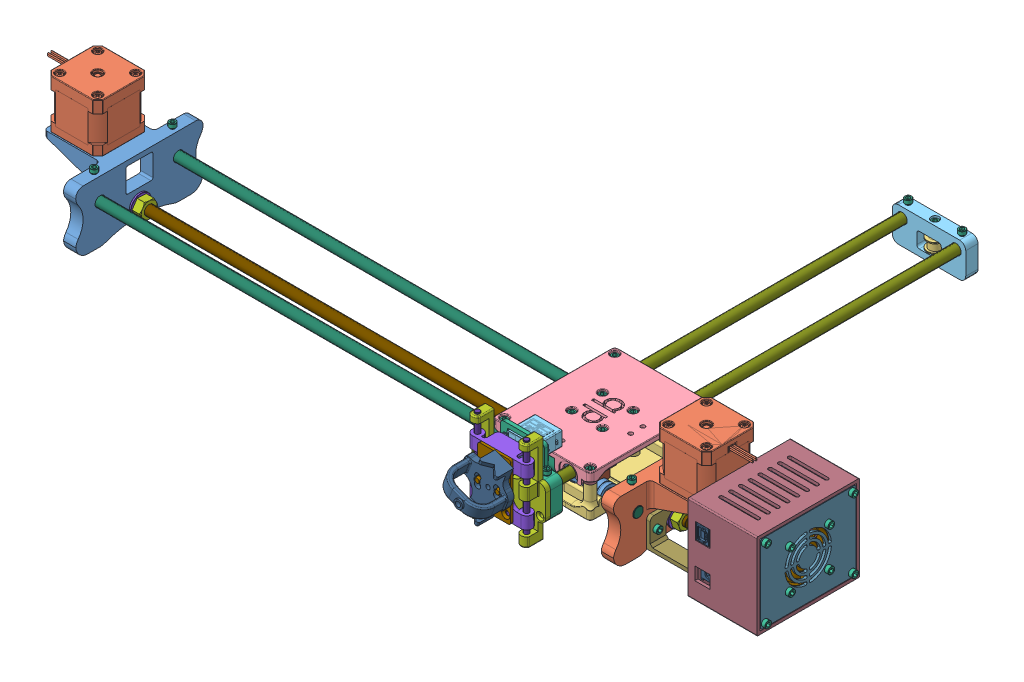
SolidWorks assembly DrawingBot, configuration 0. Lengths in mm.
Overall size (622.15 90 398.46).
88 component instances, 29 part files, 195 mates.
Components (placement in the parent):
- X_MotorHolder_R-1: X_MotorHolder_R [L=105] at (-219.5 73.7657 0) x (0 0 -1) z (1 0 0) size (103.98 50 56)
- X_MotorHolder_L-1: X_MotorHolder_L [L=105] at (219.5 73.7657 0) x (0 0 1) z (-1 0 0) size (103.98 50 56)
- Bottom_XY_Joint-1: Bottom_XY_Joint [L=105] at (163.5659 72.2657 0) x (0 0 -1) z (0 1 0) size (101.37 80.63 24)
- Top_XY_Joint-1: Top_XY_Joint [L=105] at (163.5659 106.2657 0) x (0 0 1) z (0 -1 0) size (100.63 81.5 12.75)
- Y_PullyHolder-1: Y_PullyHolder [L=105] at (163.5659 91.7657 -271.5357) x (-1 0 0) z (0 0 1) size (60 28 10)
- Y_FrontBacket-1: Y_FrontBacket [L=105] at (163.5659 91.7657 67.4643) size (60 46 10)
- Y_FrontBaseSlide-1: Y_FrontBaseSlide [L=105] at (163.5659 91.7657 74.4643) size (60 73 14)
- Y_Slider-1: Y_Slider [L=105] at (163.5659 98.6736 83.4643) size (49 46 14)
- slider-adapter-1: slider-adapter [L=105] at (163.5659 98.6736 87.4643) size (27 46 7)
- Pen_holder-1: Pen_holder [L=105] at (160.7688 99.7581 90.9643) x (-0.361491 -0.932376 0) z (0 0 1) size (46 38 29.5)
- linear bearing adapter-1: linear bearing adapter [L=105] at (185.5659 89.3657 32) x (0 0 -1) z (1 0 0) size (16 8 16)
- linear bearing adapter-2: linear bearing adapter [L=105] at (185.5659 89.3657 -32) x (0 0 -1) z (1 0 0) size (16 8 16)
- linear bearing adapter-6: linear bearing adapter [L=105] at (141.5659 89.3657 32) x (0 0 1) z (-1 0 0) size (16 8 16)
- linear bearing adapter-9: linear bearing adapter [L=105] at (141.5659 89.3657 -32) x (0 0 1) z (-1 0 0) size (16 8 16)
- ckt_Adapter-1: ckt_Adapter [L=105] at (226 74.7657 0) size (51 43.5 50)
- circuit-box-1: circuit-box [L=105] at (275.5 86.2657 0) x (0 0 -1) z (1 0 0) size (84 70 56)
- circuit-box-top-1: circuit-box-top [L=105] at (330.5 86.2657 0) x (0 0 1) z (-1 0 0) size (78 64 2.01)
- 8x450mm Rod-1: 8x450mm Rod [L=105] at (0 80.7657 32) x (0 0.981362 -0.192166) z (0 -0.192166 -0.981362) size (8 450 8)
- 8x450mm Rod-2: 8x450mm Rod [L=105] at (0 80.7657 -32) x (0 0.993096 -0.117304) z (0 -0.117304 -0.993096) size (8 450 8)
- 8x350mm Rod-1: 8x350mm Rod [L=105] at (141.5659 97.7657 -102.0357) x (0.82834 0.560225 0) z (-0.560225 0.82834 0) size (8 350 8)
- 8x350mm Rod-2: 8x350mm Rod [L=105] at (185.5659 97.7657 -102.0357) x (0.936223 -0.351406 0) z (0.351406 0.936223 0) size (8 350 8)
- 4x75mm Rod-1: 4x75mm Rod [L=105] at (143.5659 99.2657 81.9643) x (-0.999809 0 -0.019547) z (0.019547 0 -0.999809) size (4 75 4)
- 4x75mm Rod-2: 4x75mm Rod [L=105] at (183.5659 99.2657 81.9643) size (4 75 4)
- 8x470mm Threaded Rod-1: 8x470mm Threaded Rod [L=105] at (0 62.7657 0) x (0 -0.602738 0.797939) z (0 -0.797939 -0.602738) size (8 470 8)
- LM8UU-1: LM8UU [Default] at (188.8159 80.7657 -32) x (0 -0.1647 0.986344) z (-1 0 0) size (15 15 24)
- LM8UU-2: LM8UU [Default] at (138.3159 80.7657 -32) x (0 -0.602156 -0.798379) z (-1 0 0) size (15 15 24)
- LM8UU-3: LM8UU [Default] at (188.8159 80.7657 32) x (0 -0.991929 0.126791) z (-1 0 0) size (15 15 24)
- LM8UU-4: LM8UU [Default] at (138.3159 80.7657 32) x (0 -0.855569 0.517688) z (-1 0 0) size (15 15 24)
- LM8UU-5: LM8UU [Default] at (185.5659 97.7657 -35.25) x (0.052546 0.998619 0) z (0 0 -1) size (15 15 24)
- LM8UU-6: LM8UU [Default] at (185.5659 97.7657 35.25) x (-0.150221 0.988652 0) z (0 0 -1) size (15 15 24)
- LM8UU-7: LM8UU [Default] at (141.5659 97.7657 -35.25) x (-0.93295 0.360005 0) z (0 0 -1) size (15 15 24)
- LM8UU-8: LM8UU [Default] at (141.5659 97.7657 35.25) x (0.903307 0.428994 0) z (0 0 -1) size (15 15 24)
- Nema17-1: Nema17 [L=105] at (-248.5 138.7657 0) x (0 0 -1) z (0 -1 0) size (42.32 60.31 63.01)
- Nema17-2: Nema17 [L=105] at (248.5 138.7657 0) x (0 0 1) z (0 -1 0) size (42.32 60.31 63.01)
- GT2 Teethless Idler-Pulley 16TB3-1: GT2 Teethless Idler-Pulley 16TB3 [L=105] at (151.0659 89.2657 -12.5) x (-0.336139 0 0.941813) z (-0.941813 0 -0.336139) size (13 8.5 13)
- GT2 Teethless Idler-Pulley 16TB3-2: GT2 Teethless Idler-Pulley 16TB3 [L=105] at (151.0659 89.2657 12.5) x (0.130201 0 -0.991488) z (0.991488 0 0.130201) size (13 8.5 13)
- GT2 Teethless Idler-Pulley 16TB3-3: GT2 Teethless Idler-Pulley 16TB3 [L=105] at (176.0659 89.2657 12.5) x (0.290524 0 0.956868) z (-0.956868 0 0.290524) size (13 8.5 13)
- GT2 Teethless Idler-Pulley 16TB3-4: GT2 Teethless Idler-Pulley 16TB3 [L=105] at (176.0659 89.2657 -12.5) x (-0.336139 0 0.941813) z (-0.941813 0 -0.336139) size (13 8.5 13)
- GT2 Teethless Idler-Pulley 16TB3-5: GT2 Teethless Idler-Pulley 16TB3 [L=105] at (163.5659 89.2657 -271.5357) x (0.531082 0 -0.84732) z (0.84732 0 0.531082) size (13 8.5 13)
- GT Pulley T16-1: GT Pulley T16 [Default] at (-248.5 86.7657 0) x (-0.123537 0 -0.99234) z (0 1 0) size (13 13 14)
- GT Pulley T16-2: GT Pulley T16 [Default] at (248.5 86.7657 0) x (-0.763013 0 0.646383) z (0 1 0) size (13 13 14)
- SG90 - Micro Servo 9g - Tower Pro-3: SG90 - Micro Servo 9g - Tower Pro [L=105] at (170.2392 86.2325 37.9966) x (-1 0 0) z (0 1 0) size (32.5 32.03 12.58)
- M3 SCB-22: M3 SCB [5] at (185.5659 109.7657 -271.5357) x (-0.953748 0 0.300607) z (0 1 0) size (5.5 5.5 8)
- M3 SCB-24: M3 SCB [5] at (141.5659 109.7657 -271.5357) x (-0.953748 0 0.300607) z (0 1 0) size (5.5 5.5 8)
- M3 SCB-26: M3 SCB [5] at (185.5659 109.7657 67.4643) x (-0.953748 0 0.300607) z (0 1 0) size (5.5 5.5 8)
- M3 SCB-28: M3 SCB [5] at (141.5659 109.7657 67.4643) x (-0.980909 0 0.194469) z (0 1 0) size (5.5 5.5 8)
- M3 SCB-10: M3 SCB [8] at (-264 92.7657 15.5) x (0.888777 0 0.458341) z (0 -1 0) size (5.5 5.5 11)
- M3 SCB-12: M3 SCB [8] at (-233 92.7657 15.5) x (0.969011 0 0.247016) z (0 -1 0) size (5.5 5.5 11)
- M3 SCB-14: M3 SCB [8] at (-233 92.7657 -15.5) x (0.998414 0 0.056289) z (0 -1 0) size (5.5 5.5 11)
- M3 SCB-16: M3 SCB [8] at (-264 92.7657 -15.5) x (0.995991 0 -0.089455) z (0 -1 0) size (5.5 5.5 11)
- M3 SCB-4: M3 SCB [8] at (233 92.7657 -15.5) x (0.38908 0 0.921204) z (0 -1 0) size (5.5 5.5 11)
- M3 SCB-6: M3 SCB [8] at (233 92.7657 15.5) x (0.578518 0 0.815669) z (0 -1 0) size (5.5 5.5 11)
- M3 SCB-46: M3 SCB [10] at (334.5 114.7657 35.5) x (0 -0.781175 -0.624312) z (1 0 0) size (5.5 5.5 13)
- M3 SCB-47: M3 SCB [10] at (334.5 114.7657 -35.5) x (0 -0.672307 -0.740273) z (1 0 0) size (5.5 5.5 13)
- M3 SCB-49: M3 SCB [10] at (334.5 57.7657 -35.5) x (0 -0.572574 -0.819853) z (1 0 0) size (5.5 5.5 13)
- M3 SCB-51: M3 SCB [10] at (334.5 57.7657 35.5) x (0 -0.493661 -0.869655) z (1 0 0) size (5.5 5.5 13)
- M3 SCB-3: M3 SCB [12] at (264 88.7657 -15.5) x (0.575249 0 0.817979) z (0 -1 0) size (5.5 5.5 15)
- M3 SCB-8: M3 SCB [12] at (264 88.7657 15.5) x (0.997731 0 0.067327) z (0 -1 0) size (5.5 5.5 15)
- M3 SCB-59: M3 SCB [14] at (230.5 64.7657 20) x (0 -0.34953 -0.936925) z (1 0 0) size (5.5 5.5 17)
- M3 SCB-60: M3 SCB [14] at (230.5 64.7657 -20) x (0 -0.34953 -0.936925) z (1 0 0) size (5.5 5.5 17)
- M3 SCB-53: M3 SCB [15] at (334.5 102.2657 -16) x (0 -0.672307 -0.740273) z (1 0 0) size (5.5 5.5 18)
- M3 SCB-54: M3 SCB [15] at (334.5 102.2657 16) x (0 -0.54643 -0.837505) z (1 0 0) size (5.5 5.5 18)
- M3 SCB-56: M3 SCB [15] at (334.5 70.2657 -16) x (0 -0.435341 -0.900266) z (1 0 0) size (5.5 5.5 18)
- M3 SCB-58: M3 SCB [15] at (334.5 70.2657 16) x (0 -0.34953 -0.936925) z (1 0 0) size (5.5 5.5 18)
- M3 SCB-1: M3 SCB [15] at (219.5 102.7657 32) x (-0.773306 0 -0.634033) z (0 1 0) size (5.5 5.5 18)
- M3 SCB-2: M3 SCB [15] at (219.5 102.7657 -32) x (-0.981919 0 0.189303) z (0 1 0) size (5.5 5.5 18)
- M3 SCB-18: M3 SCB [15] at (-219.5 102.7657 32) x (-0.878936 0 -0.476939) z (0 1 0) size (5.5 5.5 18)
- M3 SCB-20: M3 SCB [15] at (-219.5 102.7657 -32) x (-0.961086 0 -0.27625) z (0 1 0) size (5.5 5.5 18)
- M3 SCB-45: M3 SCB [25] at (163.5659 104.7657 -271.5357) x (-0.7545 0 0.6563) z (0 1 0) size (5.5 5.5 28)
- M3 SCB-30: M3 SCB [30] at (151.0659 105.2657 -12.5) x (-0.546321 0 0.837576) z (0 1 0) size (5.5 5.5 33)
- M3 SCB-31: M3 SCB [30] at (176.0659 105.2657 -12.5) x (-0.378687 0 0.925525) z (0 1 0) size (5.5 5.5 33)
- M3 SCB-33: M3 SCB [30] at (151.0659 105.2657 12.5) x (0.82864 0 -0.559782) z (0 1 0) size (5.5 5.5 33)
- M3 SCB-35: M3 SCB [30] at (176.0659 105.2657 12.5) x (0.065489 0 0.997853) z (0 1 0) size (5.5 5.5 33)
- M3 SCB-37: M3 SCB [30] at (128.5659 105.2657 -45) x (0.402386 0 0.91547) z (0 1 0) size (5.5 5.5 33)
- M3 SCB-39: M3 SCB [30] at (198.5659 105.2657 -45) x (0.402386 0 0.91547) z (0 1 0) size (5.5 5.5 33)
- M3 SCB-41: M3 SCB [30] at (198.5659 105.2657 45) x (0.402386 0 0.91547) z (0 1 0) size (5.5 5.5 33)
- M3 SCB-43: M3 SCB [30] at (128.5659 105.2657 45) x (0.402386 0 0.91547) z (0 1 0) size (5.5 5.5 33)
- LBNR8-1: LBNR8 [L=105] at (229.25 62.7657 0) x (-1 0 0) z (0 0.682259 0.73111) size (6.5 15 13)
- LBNR8-2: LBNR8 [L=105] at (209.75 62.7657 0) x (1 0 0) z (0 0.362627 0.931934) size (6.5 15 13)
- LBNR8-4: LBNR8 [L=105] at (-229.25 62.7657 0) x (1 0 0) z (0 0.47834 0.878175) size (6.5 15 13)
- LBNR8-6: LBNR8 [L=105] at (-209.75 62.7657 0) x (-1 0 0) z (0 0.553773 0.832668) size (6.5 15 13)
- M8-Washer-1: M8-Washer [L=105] at (225.25 62.7657 0) x (0 -0.998902 0.046855) z (-1 0 0) size (17 17 1.5)
- M8-Washer-2: M8-Washer [L=105] at (213.75 62.7657 0) x (0 0.973077 0.230481) z (1 0 0) size (17 17 1.5)
- M8-Washer-4: M8-Washer [L=105] at (-225.25 62.7657 0) x (0 0.994504 0.104701) z (1 0 0) size (17 17 1.5)
- M8-Washer-6: M8-Washer [L=105] at (-213.75 62.7657 0) x (0 -0.371154 0.928571) z (-1 0 0) size (17 17 1.5)
- 40x40x10 DC Fan-1: 40x40x10 DC Fan [Default] at (324.25 86.2657 0) x (0 0 1) z (-1 0 0) size (49.86 40.69 10.5)
- arduino uno-1: arduino uno [L=105] at (281.65 62.9657 35.94) x (0 -1 0) z (0 0 1) size (53.34 15.25 74.93)
- Arduino_Uno_CNC_Shield_V3-1: Arduino_Uno_CNC_Shield_V3 [Default] at (292.66 62.9657 35.94) x (0 0 -1) z (1 0 0) size (69 53.5 27.15)
Mates (geometry in assembly coordinates):
- Concentric1: concentric anti-aligned: cylinder of X_MotorHolder_L-1 through (214.5 80.7657 32) axis (1 0 0) radius 4.2; cylinder of 8x450mm Rod-1 through (225 80.7657 32) axis (-1 0 0) radius 4
- Concentric2: concentric anti-aligned: cylinder of X_MotorHolder_L-1 through (214.5 80.7657 -32) axis (1 0 0) radius 4.2; cylinder of 8x450mm Rod-2 through (225 80.7657 -32) axis (-1 0 0) radius 4
- Concentric3: concentric aligned: cylinder of X_MotorHolder_R-1 through (-214.5 80.7657 -32) axis (-1 0 0) radius 4.2; cylinder of 8x450mm Rod-2 through (225 80.7657 -32) axis (-1 0 0) radius 4
- Concentric4: concentric aligned: cylinder of X_MotorHolder_R-1 through (-214.5 80.7657 32) axis (-1 0 0) radius 4.2; cylinder of 8x450mm Rod-1 through (225 80.7657 32) axis (-1 0 0) radius 4
- Distance1: distance = 0.5 mm aligned: plane of 8x450mm Rod-2 through (225 80.7657 -32) normal (1 0 0); plane of X_MotorHolder_L-1 through (224.5 75.0486 -66) normal (1 0 0)
- Distance2: distance = 0.5 mm aligned: plane of 8x450mm Rod-1 through (225 80.7657 32) normal (1 0 0); plane of X_MotorHolder_L-1 through (224.5 75.0486 -66) normal (1 0 0)
- Distance3: distance = 0.5 mm aligned: plane of 8x450mm Rod-2 through (-225 80.7657 -32) normal (-1 0 0); plane of X_MotorHolder_R-1 through (-224.5 75.0486 66) normal (-1 0 0)
- Concentric5: concentric anti-aligned: cylinder of 8x450mm Rod-2 through (225 80.7657 -32) axis (-1 0 0) radius 4; cylinder of LM8UU-1 through (176.8159 80.7657 -32) axis (1 0 0) radius 4
- Concentric6: concentric anti-aligned: cylinder of 8x450mm Rod-2 through (225 80.7657 -32) axis (-1 0 0) radius 4; cylinder of LM8UU-2 through (126.3159 80.7657 -32) axis (1 0 0) radius 4
- Concentric7: concentric anti-aligned: cylinder of 8x450mm Rod-1 through (225 80.7657 32) axis (-1 0 0) radius 4; cylinder of LM8UU-3 through (176.8159 80.7657 32) axis (1 0 0) radius 4
- Concentric8: concentric anti-aligned: cylinder of 8x450mm Rod-1 through (225 80.7657 32) axis (-1 0 0) radius 4; cylinder of LM8UU-4 through (126.3159 80.7657 32) axis (1 0 0) radius 4
- Concentric9: concentric anti-aligned: cylinder of LM8UU-4 through (126.3159 80.7657 32) axis (1 0 0) radius 7.5; cylinder of Bottom_XY_Joint-1 through (196.9862 80.7657 32) axis (-1 0 0) radius 7.75
- Concentric10: concentric anti-aligned: cylinder of LM8UU-2 through (126.3159 80.7657 -32) axis (1 0 0) radius 7.5; cylinder of Bottom_XY_Joint-1 through (196.9862 80.7657 -32) axis (-1 0 0) radius 7.75
- Distance4: distance = 0.25 mm anti-aligned: plane of LM8UU-2 through (126.3159 80.7657 -32) normal (-1 0 0); plane of Bottom_XY_Joint-1 through (126.0659 81.4068 -35.2499) normal (1 0 0)
- Coincident7: coincident aligned: plane of LM8UU-2 through (126.3159 80.7657 -32) normal (-1 0 0); plane of LM8UU-4 through (126.3159 80.7657 32) normal (-1 0 0)
- Distance5: distance = 0.25 mm anti-aligned: plane of Bottom_XY_Joint-1 through (201.0659 81.4068 35.2499) normal (-1 0 0); plane of LM8UU-3 through (200.8159 80.7657 32) normal (1 0 0)
- Coincident9: coincident aligned: plane of LM8UU-1 through (200.8159 80.7657 -32) normal (1 0 0); plane of LM8UU-3 through (200.8159 80.7657 32) normal (1 0 0)
- Concentric11: concentric anti-aligned: cylinder of X_MotorHolder_R-1 through (-233 94.7657 15.5) axis (0 1 0) radius 1.75; cylinder of Nema17-1 through (-233 98.7657 15.5) axis (0 -1 0) radius 1.5
- Concentric12: concentric anti-aligned: cylinder of X_MotorHolder_R-1 through (-264 94.7657 -15.5) axis (0 1 0) radius 1.75; cylinder of Nema17-1 through (-264 98.7657 -15.5) axis (0 -1 0) radius 1.5
- Coincident10: coincident anti-aligned: plane of X_MotorHolder_R-1 through (-214.5 98.7657 52) normal (0 1 0); plane of Nema17-1 through (-248.5 98.7657 0) normal (0 -1 0)
- Concentric13: concentric anti-aligned: cylinder of X_MotorHolder_L-1 through (233 94.7657 15.5) axis (0 1 0) radius 1.75; cylinder of Nema17-2 through (233 98.7657 15.5) axis (0 -1 0) radius 1.5
- Concentric14: concentric anti-aligned: cylinder of X_MotorHolder_L-1 through (264 94.7657 -15.5) axis (0 1 0) radius 1.75; cylinder of Nema17-2 through (264 98.7657 -15.5) axis (0 -1 0) radius 1.5
- Coincident11: coincident anti-aligned: plane of X_MotorHolder_L-1 through (214.5 98.7657 -52) normal (0 1 0); plane of Nema17-2 through (248.5 98.7657 0) normal (0 -1 0)
- Concentric15: concentric aligned: cylinder of Nema17-1 through (-248.5 75.7657 0) axis (0 1 0) radius 2.5; cylinder of GT Pulley T16-1 through (-248.5 111.3534 0) axis (0 1 0) radius 2.5
- Distance6: distance = 4 mm aligned: plane of GT Pulley T16-1 through (-254.9502 79.7657 0.803) normal (0 -1 0); plane of Nema17-1 through (-248.5 75.7657 0) normal (0 -1 0)
- Concentric16: concentric aligned: cylinder of Nema17-2 through (248.5 75.7657 0) axis (0 1 0) radius 2.5; cylinder of GT Pulley T16-2 through (248.5 111.3534 0) axis (0 1 0) radius 2.5
- Distance7: distance = 4 mm aligned: plane of GT Pulley T20-2 through (252.7015 79.7657 4.9596) normal (0 -1 0); plane of Nema17-2 through (248.5 75.7657 0) normal (0 -1 0)
- Concentric17: concentric aligned: cylinder of Bottom_XY_Joint-1 through (151.0659 76.2657 -12.5) axis (0 -1 0) radius 1.75; cylinder of GT2 Teethless Idler-Pulley 16TB3-1 through (151.0659 89.2657 -12.5) axis (0 -1 0) radius 1.5
- Coincident14: coincident anti-aligned: plane of Bottom_XY_Joint-1 through (151.0659 85.0157 -12.5) normal (0 1 0); plane of GT2 Teethless Idler-Pulley 16TB3-1 through (157.1877 85.0157 -10.3151) normal (0 -1 0)
- Concentric18: concentric aligned: cylinder of Bottom_XY_Joint-1 through (151.0659 76.2657 12.5) axis (0 -1 0) radius 1.75; cylinder of GT2 Teethless Idler-Pulley 16TB3-2 through (151.0659 89.2657 12.5) axis (0 -1 0) radius 1.5
- Coincident15: coincident anti-aligned: plane of Bottom_XY_Joint-1 through (151.0659 85.0157 12.5) normal (0 1 0); plane of GT2 Teethless Idler-Pulley 16TB3-2 through (144.6213 85.0157 11.6537) normal (0 -1 0)
- Concentric19: concentric aligned: cylinder of Bottom_XY_Joint-1 through (176.0659 76.2657 12.5) axis (0 -1 0) radius 1.75; cylinder of GT2 Teethless Idler-Pulley 16TB3-3 through (176.0659 89.2657 12.5) axis (0 -1 0) radius 1.5
- Concentric20: concentric aligned: cylinder of Bottom_XY_Joint-1 through (176.0659 76.2657 12.5) axis (0 -1 0) radius 1.75; cylinder of GT2 Teethless Idler-Pulley 16TB3-3 through (176.0659 89.2657 12.5) axis (0 -1 0) radius 1.5
- Coincident16: coincident anti-aligned: plane of Bottom_XY_Joint-1 through (176.0659 85.0157 12.5) normal (0 1 0); plane of GT2 Teethless Idler-Pulley 16TB3-3 through (182.2856 85.0157 10.6116) normal (0 -1 0)
- Concentric21: concentric aligned: cylinder of Bottom_XY_Joint-1 through (176.0659 76.2657 -12.5) axis (0 -1 0) radius 1.75; cylinder of GT2 Teethless Idler-Pulley 16TB3-4 through (176.0659 89.2657 -12.5) axis (0 -1 0) radius 1.5
- Coincident17: coincident anti-aligned: plane of Bottom_XY_Joint-1 through (176.0659 85.0157 -12.5) normal (0 1 0); plane of GT2 Teethless Idler-Pulley 16TB3-4 through (182.1877 85.0157 -10.3151) normal (0 -1 0)
- Concentric22: concentric aligned: cylinder of LM8UU-6 through (185.5659 97.7657 23.25) axis (0 0 1) radius 7.5; cylinder of Top_XY_Joint-1 through (185.5659 97.7657 -43.4203) axis (0 0 1) radius 7.75
- Concentric23: concentric anti-aligned: cylinder of LM8UU-5 through (185.5659 97.7657 -47.25) axis (0 0 1) radius 7.5; cylinder of Top_XY_Joint-1 through (185.5659 97.7657 0.4203) axis (0 0 -1) radius 7.75
- Concentric24: concentric aligned: cylinder of LM8UU-8 through (141.5659 97.7657 23.25) axis (0 0 1) radius 7.5; cylinder of Top_XY_Joint-1 through (141.5659 97.7657 -43.4203) axis (0 0 1) radius 7.75
- Concentric25: concentric anti-aligned: cylinder of LM8UU-7 through (141.5659 97.7657 -47.25) axis (0 0 1) radius 7.5; cylinder of Top_XY_Joint-1 through (141.5659 97.7657 0.4203) axis (0 0 -1) radius 7.75
- Distance8: distance = 0.25 mm anti-aligned: plane of Top_XY_Joint-1 through (188.8158 97.1246 -47.5) normal (0 0 1); plane of LM8UU-5 through (185.5659 97.7657 -47.25) normal (0 0 -1)
- Coincident19: coincident aligned: plane of LM8UU-5 through (185.5659 97.7657 -47.25) normal (0 0 -1); plane of LM8UU-7 through (141.5659 97.7657 -47.25) normal (0 0 -1)
- Distance9: distance = 0.25 mm anti-aligned: plane of LM8UU-8 through (141.5659 97.7657 47.25) normal (0 0 1); plane of Top_XY_Joint-1 through (138.3161 97.1246 47.5) normal (0 0 -1)
- Coincident21: coincident aligned: plane of LM8UU-6 through (185.5659 97.7657 47.25) normal (0 0 1); plane of LM8UU-8 through (141.5659 97.7657 47.25) normal (0 0 1)
- Concentric26: concentric anti-aligned: cylinder of Bottom_XY_Joint-1 through (198.5659 72.2657 45) axis (0 1 0) radius 1.75; cylinder of Top_XY_Joint-1 through (198.5659 106.2657 45) axis (0 -1 0) radius 1.75
- Concentric27: concentric anti-aligned: cylinder of Bottom_XY_Joint-1 through (128.5659 72.2657 -45) axis (0 1 0) radius 1.75; cylinder of Top_XY_Joint-1 through (128.5659 106.2657 -45) axis (0 -1 0) radius 1.75
- Coincident22: coincident anti-aligned: plane of Bottom_XY_Joint-1 through (128.5659 96.2657 -45) normal (0 1 0); plane of Top_XY_Joint-1 through (128.5659 96.2657 -45) normal (0 -1 0)
- Concentric28: concentric aligned: cylinder of LM8UU-7 through (141.5659 97.7657 -47.25) axis (0 0 1) radius 4; cylinder of 8x350mm Rod-1 through (141.5659 97.7657 -277.0357) axis (0 0 1) radius 4
- Concentric29: concentric aligned: cylinder of LM8UU-8 through (141.5659 97.7657 23.25) axis (0 0 1) radius 4; cylinder of 8x350mm Rod-1 through (141.5659 97.7657 -277.0357) axis (0 0 1) radius 4
- Concentric30: concentric aligned: cylinder of LM8UU-5 through (185.5659 97.7657 -47.25) axis (0 0 1) radius 4; cylinder of 8x350mm Rod-2 through (185.5659 97.7657 -277.0357) axis (0 0 1) radius 4
- Concentric31: concentric aligned: cylinder of LM8UU-6 through (185.5659 97.7657 23.25) axis (0 0 1) radius 4; cylinder of 8x350mm Rod-2 through (185.5659 97.7657 -277.0357) axis (0 0 1) radius 4
- Coincident23: coincident aligned: plane of 8x350mm Rod-1 through (141.5659 97.7657 72.9643) normal (0 0 1); plane of 8x350mm Rod-2 through (185.5659 97.7657 72.9643) normal (0 0 1)
- Concentric32: concentric anti-aligned: cylinder of X_MotorHolder_R-1 through (-214.5 62.7657 0) axis (-1 0 0) radius 4.2; cylinder of 8x470mm Threaded Rod-1 through (-235 62.7657 0) axis (1 0 0) radius 4
- Concentric33: concentric anti-aligned: cylinder of 8x350mm Rod-2 through (185.5659 97.7657 -277.0357) axis (0 0 1) radius 4; cylinder of Y_PullyHolder-1 through (185.5659 97.7657 -266.5357) axis (0 0 -1) radius 4.25
- Concentric35: concentric anti-aligned: cylinder of 8x350mm Rod-1 through (141.5659 97.7657 -277.0357) axis (0 0 1) radius 4; cylinder of Y_PullyHolder-1 through (141.5659 97.7657 -266.5357) axis (0 0 -1) radius 4.25
- Concentric36: concentric aligned: cylinder of Y_PullyHolder-1 through (163.5659 107.7657 -271.5357) axis (0 -1 0) radius 1.75; cylinder of GT2 Teethless Idler-Pulley 16TB3-5 through (163.5659 89.2657 -271.5357) axis (0 -1 0) radius 1.5
- Distance10: distance = 2 mm anti-aligned: plane of GT2 Teethless Idler-Pulley 16TB3-5 through (162.295 93.5157 -272.3323) normal (0 1 0); plane of Y_PullyHolder-1 through (173.5659 95.5157 -266.5357) normal (0 -1 0)
- Distance11: distance = 0.5 mm aligned: plane of Y_PullyHolder-1 through (163.5659 91.7657 -276.5357) normal (0 0 -1); plane of 8x350mm Rod-2 through (185.5659 97.7657 -277.0357) normal (0 0 -1)
- Concentric37: concentric anti-aligned: cylinder of 8x350mm Rod-1 through (141.5659 97.7657 -277.0357) axis (0 0 1) radius 4; cylinder of Y_FrontBacket-1 through (141.5659 97.7657 72.4643) axis (0 0 -1) radius 4.25
- Concentric38: concentric anti-aligned: cylinder of 8x350mm Rod-2 through (185.5659 97.7657 -277.0357) axis (0 0 1) radius 4; cylinder of Y_FrontBacket-1 through (185.5659 97.7657 72.4643) axis (0 0 -1) radius 4.25
- Distance12: distance = 0.5 mm aligned: plane of 8x350mm Rod-1 through (141.5659 97.7657 72.9643) normal (0 0 1); plane of Y_FrontBacket-1 through (163.5659 91.7657 72.4643) normal (0 0 1)
- Concentric42: concentric: cylinder of Y_FrontBacket-1 through (138.0659 82.2657 62.4643) axis (0 0 1) radius 1.75; cylinder of Y_FrontBaseSlide-1 through (138.0659 82.2657 76.4643) axis (0 0 1) radius 1.7
- Concentric43: concentric: cylinder of Y_FrontBacket-1 through (189.0659 82.2657 62.4643) axis (0 0 1) radius 1.75; cylinder of Y_FrontBaseSlide-1 through (189.0659 82.2657 76.4643) axis (0 0 1) radius 1.7
- Coincident26: coincident: plane of Y_FrontBacket-1 through (163.5659 91.7657 72.4643) normal (0 0 1); plane of Y_FrontBaseSlide-1 through (163.5659 117.7657 72.4643) normal (0 0 -1)
- Concentric44: concentric aligned: cylinder of Y_FrontBaseSlide-1 through (143.5659 130.7657 81.9643) axis (0 1 0) radius 2.05; cylinder of Y_Slider-1 through (143.5659 111.6736 81.9643) axis (0 1 0) radius 2.1
- Concentric45: concentric aligned: cylinder of Y_FrontBaseSlide-1 through (183.5659 130.7657 81.9643) axis (0 1 0) radius 2.05; cylinder of Y_Slider-1 through (183.5659 111.6736 81.9643) axis (0 1 0) radius 2.1
- Concentric46: concentric anti-aligned: cylinder of Y_FrontBaseSlide-1 through (143.5659 130.7657 81.9643) axis (0 1 0) radius 2.05; cylinder of 4x75mm Rod-1 through (143.5659 136.7657 81.9643) axis (0 -1 0) radius 2
- Distance13: distance = 1 mm aligned: plane of Y_FrontBaseSlide-1 through (147.5659 135.7657 149.9014) normal (0 1 0); plane of 4x75mm Rod-1 through (143.5659 136.7657 81.9643) normal (0 1 0)
- Concentric47: concentric anti-aligned: cylinder of Y_FrontBaseSlide-1 through (183.5659 130.7657 81.9643) axis (0 1 0) radius 2.05; cylinder of 4x75mm Rod-2 through (183.5659 136.7657 81.9643) axis (0 -1 0) radius 2
- Distance14: distance = 1 mm aligned: plane of Y_FrontBaseSlide-1 through (187.5659 135.7657 149.9014) normal (0 1 0); plane of 4x75mm Rod-2 through (183.5659 136.7657 81.9643) normal (0 1 0)
- Concentric49: concentric aligned: cylinder of X_MotorHolder_L-1 through (219.5 48.7647 32) axis (0 1 0) radius 1.75; cylinder of M3 SCB-1 through (219.5 122.7657 32) axis (0 1 0) radius 1.5
- Tangent2: tangent anti-aligned: cylinder of 8x450mm Rod-1 through (225 80.7657 32) axis (-1 0 0) radius 4; plane of M3 SCB-1 through (220.66 84.7657 32.951) normal (0 -1 0)
- Concentric51: concentric aligned: cylinder of X_MotorHolder_L-1 through (219.5 94.7657 -32) axis (0 1 0) radius 2.1; cylinder of M3 SCB-2 through (219.5 122.7657 -32) axis (0 1 0) radius 1.5
- Tangent4: tangent anti-aligned: cylinder of 8x450mm Rod-2 through (225 80.7657 -32) axis (-1 0 0) radius 4; plane of M3 SCB-2 through (220.9729 84.7657 -32.284) normal (0 -1 0)
- Concentric52: concentric anti-aligned: cylinder of X_MotorHolder_L-1 through (264 94.7657 -15.5) axis (0 1 0) radius 1.75; cylinder of M3 SCB-3 through (264 68.7657 -15.5) axis (0 -1 0) radius 1.5
- Concentric53: concentric anti-aligned: cylinder of X_MotorHolder_L-1 through (233 94.7657 -15.5) axis (0 1 0) radius 1.75; cylinder of M3 SCB-4 through (233 72.7657 -15.5) axis (0 -1 0) radius 1.5
- Coincident32: coincident anti-aligned: plane of X_MotorHolder_L-1 through (233 95.7657 -15.5) normal (0 -1 0); plane of M3 SCB-4 through (231.93 95.7657 -18.0333) normal (0 1 0)
- Concentric54: concentric anti-aligned: cylinder of X_MotorHolder_L-1 through (233 94.7657 15.5) axis (0 1 0) radius 1.75; cylinder of M3 SCB-6 through (233 72.7657 15.5) axis (0 -1 0) radius 1.5
- Coincident33: coincident anti-aligned: plane of X_MotorHolder_L-1 through (233 95.7657 15.5) normal (0 -1 0); plane of M3 SCB-6 through (231.4091 95.7657 13.2569) normal (0 1 0)
- Concentric55: concentric anti-aligned: cylinder of X_MotorHolder_L-1 through (264 94.7657 15.5) axis (0 1 0) radius 1.75; cylinder of M3 SCB-8 through (264 68.7657 15.5) axis (0 -1 0) radius 1.5
- Concentric56: concentric anti-aligned: cylinder of X_MotorHolder_R-1 through (-264 94.7657 15.5) axis (0 1 0) radius 1.75; cylinder of M3 SCB-10 through (-264 72.7657 15.5) axis (0 -1 0) radius 1.5
- Coincident35: coincident anti-aligned: plane of X_MotorHolder_R-1 through (-264 95.7657 15.5) normal (0 -1 0); plane of M3 SCB-10 through (-266.4441 95.7657 14.2396) normal (0 1 0)
- Concentric57: concentric anti-aligned: cylinder of X_MotorHolder_R-1 through (-233 94.7657 15.5) axis (0 1 0) radius 1.75; cylinder of M3 SCB-12 through (-233 72.7657 15.5) axis (0 -1 0) radius 1.5
- Coincident36: coincident anti-aligned: plane of X_MotorHolder_R-1 through (-233 95.7657 15.5) normal (0 -1 0); plane of M3 SCB-12 through (-235.6648 95.7657 14.8207) normal (0 1 0)
- Concentric58: concentric anti-aligned: cylinder of X_MotorHolder_R-1 through (-233 94.7657 -15.5) axis (0 1 0) radius 1.75; cylinder of M3 SCB-14 through (-233 72.7657 -15.5) axis (0 -1 0) radius 1.5
- Coincident37: coincident anti-aligned: plane of X_MotorHolder_R-1 through (-233 95.7657 -15.5) normal (0 -1 0); plane of M3 SCB-14 through (-235.7456 95.7657 -15.6548) normal (0 1 0)
- Concentric59: concentric anti-aligned: cylinder of X_MotorHolder_R-1 through (-264 94.7657 -15.5) axis (0 1 0) radius 1.75; cylinder of M3 SCB-16 through (-264 72.7657 -15.5) axis (0 -1 0) radius 1.5
- Coincident38: coincident anti-aligned: plane of X_MotorHolder_R-1 through (-264 95.7657 -15.5) normal (0 -1 0); plane of M3 SCB-16 through (-266.739 95.7657 -15.254) normal (0 1 0)
- Concentric60: concentric aligned: cylinder of X_MotorHolder_R-1 through (-219.5 48.7647 32) axis (0 1 0) radius 1.75; cylinder of M3 SCB-18 through (-219.5 122.7657 32) axis (0 1 0) radius 1.5
- Tangent5: tangent anti-aligned: cylinder of 8x450mm Rod-1 through (225 80.7657 32) axis (-1 0 0) radius 4; plane of M3 SCB-18 through (-218.1816 84.7657 32.7154) normal (0 -1 0)
- Concentric61: concentric aligned: cylinder of X_MotorHolder_R-1 through (-219.5 48.7647 -32) axis (0 1 0) radius 1.75; cylinder of M3 SCB-20 through (-219.5 122.7657 -32) axis (0 1 0) radius 1.5
- Tangent6: tangent anti-aligned: cylinder of 8x450mm Rod-2 through (225 80.7657 -32) axis (-1 0 0) radius 4; plane of M3 SCB-20 through (-218.0584 84.7657 -31.5856) normal (0 -1 0)
- Concentric62: concentric anti-aligned: cylinder of Y_PullyHolder-1 through (185.5659 77.7647 -271.5357) axis (0 -1 0) radius 1.75; cylinder of M3 SCB-22 through (185.5659 129.7657 -271.5357) axis (0 1 0) radius 1.5
- Tangent7: tangent anti-aligned: cylinder of 8x350mm Rod-2 through (185.5659 97.7657 -277.0357) axis (0 0 1) radius 4; plane of M3 SCB-22 through (186.9966 101.7657 -271.9866) normal (0 -1 0)
- Concentric63: concentric anti-aligned: cylinder of Y_PullyHolder-1 through (141.5659 77.7647 -271.5357) axis (0 -1 0) radius 1.75; cylinder of M3 SCB-24 through (141.5659 129.7657 -271.5357) axis (0 1 0) radius 1.5
- Tangent8: tangent anti-aligned: cylinder of 8x350mm Rod-1 through (141.5659 97.7657 -277.0357) axis (0 0 1) radius 4; plane of M3 SCB-24 through (142.9966 101.7657 -271.9866) normal (0 -1 0)
- Concentric64: concentric anti-aligned: cylinder of Y_FrontBacket-1 through (185.5659 77.7647 67.4643) axis (0 -1 0) radius 1.75; cylinder of M3 SCB-26 through (185.5659 129.7657 67.4643) axis (0 1 0) radius 1.5
- Tangent9: tangent anti-aligned: cylinder of 8x350mm Rod-2 through (185.5659 97.7657 -277.0357) axis (0 0 1) radius 4; plane of M3 SCB-26 through (186.9966 101.7657 67.0134) normal (0 -1 0)
- Concentric65: concentric anti-aligned: cylinder of Y_FrontBacket-1 through (141.5659 77.7647 67.4643) axis (0 -1 0) radius 1.75; cylinder of M3 SCB-28 through (141.5659 129.7657 67.4643) axis (0 1 0) radius 1.5
- Tangent10: tangent anti-aligned: cylinder of 8x350mm Rod-1 through (141.5659 97.7657 -277.0357) axis (0 0 1) radius 4; plane of M3 SCB-28 through (143.0373 101.7657 67.1726) normal (0 -1 0)
- Concentric66: concentric aligned: cylinder of Top_XY_Joint-1 through (151.0659 102.2657 -12.5) axis (0 1 0) radius 1.75; cylinder of M3 SCB-30 through (151.0659 125.2657 -12.5) axis (0 1 0) radius 1.5
- Coincident39: coincident anti-aligned: plane of Top_XY_Joint-1 through (151.0659 102.2657 -12.5) normal (0 1 0); plane of M3 SCB-30 through (152.5683 102.2657 -14.8033) normal (0 -1 0)
- Concentric67: concentric aligned: cylinder of Top_XY_Joint-1 through (176.0659 102.2657 -12.5) axis (0 1 0) radius 1.75; cylinder of M3 SCB-31 through (176.0659 125.2657 -12.5) axis (0 1 0) radius 1.5
- Coincident40: coincident anti-aligned: plane of Top_XY_Joint-1 through (176.0659 102.2657 -12.5) normal (0 1 0); plane of M3 SCB-31 through (177.1073 102.2657 -15.0452) normal (0 -1 0)
- Concentric68: concentric aligned: cylinder of Top_XY_Joint-1 through (151.0659 102.2657 12.5) axis (0 1 0) radius 1.75; cylinder of M3 SCB-33 through (151.0659 125.2657 12.5) axis (0 1 0) radius 1.5
- Coincident41: coincident anti-aligned: plane of Top_XY_Joint-1 through (151.0659 102.2657 12.5) normal (0 1 0); plane of M3 SCB-33 through (148.7872 102.2657 14.0394) normal (0 -1 0)
- Concentric69: concentric aligned: cylinder of Top_XY_Joint-1 through (176.0659 102.2657 12.5) axis (0 1 0) radius 1.75; cylinder of M3 SCB-35 through (176.0659 125.2657 12.5) axis (0 1 0) radius 1.5
- Coincident42: coincident anti-aligned: plane of Top_XY_Joint-1 through (176.0659 102.2657 12.5) normal (0 1 0); plane of M3 SCB-35 through (175.8858 102.2657 9.7559) normal (0 -1 0)
- Concentric70: concentric anti-aligned: cylinder of Top_XY_Joint-1 through (128.5659 106.2657 -45) axis (0 -1 0) radius 1.75; cylinder of M3 SCB-37 through (128.5659 125.2657 -45) axis (0 1 0) radius 1.5
- Coincident43: coincident anti-aligned: plane of Top_XY_Joint-1 through (128.5659 102.2657 -45) normal (0 1 0); plane of M3 SCB-37 through (127.4594 102.2657 -47.5175) normal (0 -1 0)
- Concentric71: concentric anti-aligned: cylinder of Top_XY_Joint-1 through (198.5659 106.2657 -45) axis (0 -1 0) radius 1.75; cylinder of M3 SCB-39 through (198.5659 125.2657 -45) axis (0 1 0) radius 1.5
- Coincident44: coincident anti-aligned: plane of Top_XY_Joint-1 through (198.5659 102.2657 -45) normal (0 1 0); plane of M3 SCB-39 through (197.4594 102.2657 -47.5175) normal (0 -1 0)
- Concentric72: concentric anti-aligned: cylinder of Top_XY_Joint-1 through (198.5659 106.2657 45) axis (0 -1 0) radius 1.75; cylinder of M3 SCB-41 through (198.5659 125.2657 45) axis (0 1 0) radius 1.5
- Coincident45: coincident anti-aligned: plane of Top_XY_Joint-1 through (198.5659 102.2657 45) normal (0 1 0); plane of M3 SCB-41 through (197.4594 102.2657 42.4825) normal (0 -1 0)
- Concentric73: concentric anti-aligned: cylinder of Top_XY_Joint-1 through (128.5659 106.2657 45) axis (0 -1 0) radius 1.75; cylinder of M3 SCB-43 through (128.5659 125.2657 45) axis (0 1 0) radius 1.5
- Coincident46: coincident anti-aligned: plane of Top_XY_Joint-1 through (128.5659 102.2657 45) normal (0 1 0); plane of M3 SCB-43 through (127.4594 102.2657 42.4825) normal (0 -1 0)
- Concentric74: concentric anti-aligned: cylinder of Y_PullyHolder-1 through (163.5659 107.7657 -271.5357) axis (0 -1 0) radius 1.75; cylinder of M3 SCB-45 through (163.5659 124.7657 -271.5357) axis (0 1 0) radius 1.5
- Coincident47: coincident anti-aligned: plane of Y_PullyHolder-1 through (163.5659 101.7657 -271.5357) normal (0 1 0); plane of M3 SCB-45 through (165.6408 101.7657 -273.3405) normal (0 -1 0)
- Concentric77: concentric anti-aligned: cylinder of 8x470mm Threaded Rod-1 through (-235 62.7657 0) axis (1 0 0) radius 4; cylinder of LBNR8-1 through (226 62.7657 0) axis (-1 0 0) radius 3.3235
- Concentric78: concentric anti-aligned: cylinder of 8x470mm Threaded Rod-1 through (-235 62.7657 0) axis (1 0 0) radius 4; cylinder of M8-Washer-1 through (225.25 62.7657 0) axis (-1 0 0) radius 4.2
- Coincident50: coincident anti-aligned: plane of LBNR8-1 through (226 57.2824 5.1169) normal (-1 0 0); plane of M8-Washer-1 through (226 58.5703 0.1968) normal (1 0 0)
- Coincident51: coincident anti-aligned: plane of X_MotorHolder_L-1 through (224.5 75.0486 -66) normal (1 0 0); plane of M8-Washer-1 through (224.5 58.5703 0.1968) normal (-1 0 0)
- Coincident52: coincident anti-aligned: plane of LBNR8-2 through (213 69.7552 -2.7197) normal (1 0 0); plane of M8-Washer-2 through (213 66.8526 0.968) normal (-1 0 0)
- Concentric79: concentric aligned: cylinder of 8x470mm Threaded Rod-1 through (-235 62.7657 0) axis (1 0 0) radius 4; cylinder of LBNR8-2 through (213 62.7657 0) axis (1 0 0) radius 3.3235
- Concentric80: concentric aligned: cylinder of 8x470mm Threaded Rod-1 through (-235 62.7657 0) axis (1 0 0) radius 4; cylinder of M8-Washer-2 through (213.75 62.7657 0) axis (1 0 0) radius 4.2
- Coincident53: coincident anti-aligned: plane of X_MotorHolder_L-1 through (214.5 75.0486 -66) normal (-1 0 0); plane of M8-Washer-2 through (214.5 66.8526 0.968) normal (1 0 0)
- Coincident55: coincident anti-aligned: plane of LBNR8-4 through (-226 69.352 -3.5876) normal (1 0 0); plane of M8-Washer-4 through (-226 66.9426 0.4397) normal (-1 0 0)
- Concentric81: concentric aligned: cylinder of 8x470mm Threaded Rod-1 through (-235 62.7657 0) axis (1 0 0) radius 4; cylinder of M8-Washer-4 through (-225.25 62.7657 0) axis (1 0 0) radius 4.2
- Concentric82: concentric aligned: cylinder of 8x470mm Threaded Rod-1 through (-235 62.7657 0) axis (1 0 0) radius 4; cylinder of LBNR8-4 through (-226 62.7657 0) axis (1 0 0) radius 3.3235
- Coincident56: coincident anti-aligned: plane of X_MotorHolder_R-1 through (-224.5 75.0486 66) normal (-1 0 0); plane of M8-Washer-4 through (-224.5 66.9426 0.4397) normal (1 0 0)
- Coincident58: coincident anti-aligned: plane of LBNR8-6 through (-213 56.5207 4.1533) normal (-1 0 0); plane of M8-Washer-6 through (-213 61.2069 3.9) normal (1 0 0)
- Concentric83: concentric anti-aligned: cylinder of 8x470mm Threaded Rod-1 through (-235 62.7657 0) axis (1 0 0) radius 4; cylinder of LBNR8-6 through (-213 62.7657 0) axis (-1 0 0) radius 3.3235
- Concentric84: concentric anti-aligned: cylinder of 8x470mm Threaded Rod-1 through (-235 62.7657 0) axis (1 0 0) radius 4; cylinder of M8-Washer-6 through (-213.75 62.7657 0) axis (-1 0 0) radius 4.2
- Coincident59: coincident anti-aligned: plane of X_MotorHolder_R-1 through (-214.5 75.0486 66) normal (1 0 0); plane of M8-Washer-6 through (-214.5 61.2069 3.9) normal (-1 0 0)
- Distance15: distance = 2.5 mm aligned: plane of 8x470mm Threaded Rod-1 through (-235 62.7657 0) normal (-1 0 0); plane of LBNR8-4 through (-232.5 62.7657 0) normal (-1 0 0)
- Concentric85: concentric anti-aligned: cylinder of LM8UU-3 through (176.8159 80.7657 32) axis (1 0 0) radius 7.5; cylinder of linear bearing adapter-1 through (193.5659 80.7657 32) axis (-1 0 0) radius 7.6
- Parallel4: parallel aligned: plane of Top_XY_Joint-1 through (126.5659 102.2657 50) normal (0 0 1); plane of linear bearing adapter-1 through (193.5659 93.3657 40) normal (0 0 1)
- Distance16: distance = 0.75 mm aligned: plane of linear bearing adapter-1 through (177.5659 80.7657 32) normal (-1 0 0); plane of LM8UU-3 through (176.8159 80.7657 32) normal (-1 0 0)
- Concentric93: concentric anti-aligned: cylinder of LM8UU-1 through (176.8159 80.7657 -32) axis (1 0 0) radius 7.5; cylinder of linear bearing adapter-2 through (193.5659 80.7657 -32) axis (-1 0 0) radius 7.6
- Parallel6: parallel aligned: plane of LM8UU-5 through (185.5659 97.7657 -23.25) normal (0 0 1); plane of linear bearing adapter-2 through (193.5659 93.3657 -24) normal (0 0 1)
- Distance17: distance = 0.75 mm aligned: plane of linear bearing adapter-2 through (177.5659 80.7657 -32) normal (-1 0 0); plane of LM8UU-1 through (176.8159 80.7657 -32) normal (-1 0 0)
- Concentric96: concentric aligned: cylinder of LM8UU-4 through (126.3159 80.7657 32) axis (1 0 0) radius 7.5; cylinder of linear bearing adapter-6 through (133.5659 80.7657 32) axis (1 0 0) radius 7.6
- Parallel12: parallel anti-aligned: plane of Top_XY_Joint-1 through (126.5659 102.2657 50) normal (0 0 1); plane of linear bearing adapter-6 through (133.5659 93.3657 24) normal (0 0 -1)
- Distance19: distance = 0.75 mm aligned: plane of linear bearing adapter-6 through (149.5659 80.7657 32) normal (1 0 0); plane of LM8UU-4 through (150.3159 80.7657 32) normal (1 0 0)
- Concentric98: concentric aligned: cylinder of LM8UU-2 through (126.3159 80.7657 -32) axis (1 0 0) radius 7.5; cylinder of linear bearing adapter-9 through (133.5659 80.7657 -32) axis (1 0 0) radius 7.6
- Parallel17: parallel aligned: plane of Top_XY_Joint-1 through (126.5659 102.2657 -50) normal (0 0 -1); plane of linear bearing adapter-9 through (133.5659 93.3657 -40) normal (0 0 -1)
- Distance20: distance = 0.75 mm aligned: plane of linear bearing adapter-9 through (149.5659 80.7657 -32) normal (1 0 0); plane of LM8UU-2 through (150.3159 80.7657 -32) normal (1 0 0)
- Concentric101: concentric aligned: cylinder of X_MotorHolder_L-1 through (270.5 64.7657 20) axis (-1 0 0) radius 1.75; cylinder of ckt_Adapter-1 through (232.4497 64.7657 20) axis (-1 0 0) radius 1.75
- Concentric102: concentric aligned: cylinder of X_MotorHolder_L-1 through (270.5 64.7657 -20) axis (-1 0 0) radius 1.75; cylinder of ckt_Adapter-1 through (232.4497 64.7657 -20) axis (-1 0 0) radius 1.75
- Coincident61: coincident anti-aligned: plane of X_MotorHolder_L-1 through (224.5 75.0486 -66) normal (1 0 0); plane of ckt_Adapter-1 through (224.5 74.7657 25) normal (-1 0 0)
- Concentric103: concentric aligned: cylinder of Y_Slider-1 through (163.5659 115.6736 86.4643) axis (0 0 -1) radius 1.75; cylinder of slider-adapter-1 through (163.5659 115.6736 88.4643) axis (0 0 -1) radius 1.75
- Concentric104: concentric aligned: cylinder of Y_Slider-1 through (173.0659 81.6736 86.4643) axis (0 0 -1) radius 1.75; cylinder of slider-adapter-1 through (173.0659 81.6736 88.4643) axis (0 0 -1) radius 1.75
- Coincident62: coincident anti-aligned: plane of Y_Slider-1 through (133.5382 98.6736 86.4643) normal (0 0 1); plane of slider-adapter-1 through (163.5659 98.6736 86.4643) normal (0 0 -1)
- Concentric105: concentric anti-aligned: cylinder of Pen_holder-1 through (163.5659 98.6736 90.4643) axis (0 0 1) radius 1.75; cylinder of slider-adapter-1 through (163.5659 98.6736 93.4643) axis (0 0 -1) radius 3
- Coincident63: coincident anti-aligned: plane of Pen_holder-1 through (140.6378 89.3301 88.4643) normal (0 0 -1); plane of slider-adapter-1 through (163.5659 98.6736 88.4643) normal (0 0 1)
- Coincident64: coincident anti-aligned: plane of ckt_Adapter-1 through (275.5 52.7657 25) normal (1 0 0); plane of circuit-box-1 through (275.5 86.2657 0) normal (-1 0 0)
- Concentric106: concentric aligned: cylinder of ckt_Adapter-1 through (224.499 59.2657 18) axis (1 0 0) radius 1.75; cylinder of circuit-box-1 through (278 59.2657 18) axis (1 0 0) radius 1.7
- Concentric107: concentric aligned: cylinder of ckt_Adapter-1 through (224.499 84.2657 -18) axis (1 0 0) radius 1.75; cylinder of circuit-box-1 through (278 84.2657 -18) axis (1 0 0) radius 1.7
- Concentric109: concentric aligned: cylinder of circuit-box-1 through (326.5 114.7657 35.5) axis (1 0 0) radius 2.1; cylinder of circuit-box-top-1 through (329.5 114.7657 35.5) axis (1 0 0) radius 1.75
- Concentric114: concentric aligned: cylinder of circuit-box-1 through (326.5 57.7657 -35.5) axis (1 0 0) radius 2.1; cylinder of circuit-box-top-1 through (329.5 57.7657 -35.5) axis (1 0 0) radius 1.75
- Coincident65: coincident anti-aligned: plane of circuit-box-1 through (329.5 113.7657 34.5) normal (1 0 0); plane of circuit-box-top-1 through (329.5 56.2657 -37) normal (-1 0 0)
- Concentric115: concentric aligned: cylinder of circuit-box-top-1 through (331.5 102.2657 -16) axis (-1 0 0) radius 1.75; cylinder of 40x40x10 DC Fan-1 through (319 102.2657 -16) axis (-1 0 0) radius 1.725
- Concentric116: concentric aligned: cylinder of circuit-box-top-1 through (331.5 70.2657 16) axis (-1 0 0) radius 1.75; cylinder of 40x40x10 DC Fan-1 through (319 70.2657 16) axis (-1 0 0) radius 1.725
- Coincident66: coincident anti-aligned: plane of circuit-box-top-1 through (329.5 56.2657 -37) normal (-1 0 0); plane of 40x40x10 DC Fan-1 through (329.5 70.2657 -16) normal (1 0 0)
- Concentric117: concentric aligned: cylinder of circuit-box-top-1 through (329.5 114.7657 35.5) axis (1 0 0) radius 1.75; cylinder of M3 SCB-46 through (354.5 114.7657 35.5) axis (1 0 0) radius 1.5
- Coincident67: coincident anti-aligned: plane of circuit-box-top-1 through (331.5 56.2657 -37) normal (1 0 0); plane of M3 SCB-46 through (331.5 116.9139 37.2169) normal (-1 0 0)
- Concentric118: concentric aligned: cylinder of circuit-box-top-1 through (329.5 114.7657 -35.5) axis (1 0 0) radius 1.75; cylinder of M3 SCB-47 through (354.5 114.7657 -35.5) axis (1 0 0) radius 1.5
- Coincident68: coincident anti-aligned: plane of circuit-box-top-1 through (331.5 56.2657 -37) normal (1 0 0); plane of M3 SCB-47 through (331.5 116.6145 -33.4643) normal (-1 0 0)
- Concentric119: concentric aligned: cylinder of circuit-box-top-1 through (329.5 57.7657 -35.5) axis (1 0 0) radius 1.75; cylinder of M3 SCB-49 through (354.5 57.7657 -35.5) axis (1 0 0) radius 1.5
- Coincident69: coincident anti-aligned: plane of circuit-box-top-1 through (331.5 56.2657 -37) normal (1 0 0); plane of M3 SCB-49 through (331.5 59.3403 -33.2454) normal (-1 0 0)
- Concentric120: concentric aligned: cylinder of circuit-box-top-1 through (329.5 57.7657 35.5) axis (1 0 0) radius 1.75; cylinder of M3 SCB-51 through (354.5 57.7657 35.5) axis (1 0 0) radius 1.5
- Coincident70: coincident anti-aligned: plane of circuit-box-top-1 through (331.5 56.2657 -37) normal (1 0 0); plane of M3 SCB-51 through (331.5 59.1233 37.8916) normal (-1 0 0)
- Concentric121: concentric anti-aligned: cylinder of circuit-box-top-1 through (331.5 102.2657 -16) axis (-1 0 0) radius 1.75; cylinder of M3 SCB-53 through (354.5 102.2657 -16) axis (1 0 0) radius 1.5
- Coincident71: coincident anti-aligned: plane of circuit-box-top-1 through (331.5 56.2657 -37) normal (1 0 0); plane of M3 SCB-53 through (331.5 104.1145 -13.9643) normal (-1 0 0)
- Concentric122: concentric anti-aligned: cylinder of circuit-box-top-1 through (331.5 102.2657 16) axis (-1 0 0) radius 1.75; cylinder of M3 SCB-54 through (354.5 102.2657 16) axis (1 0 0) radius 1.5
- Coincident72: coincident anti-aligned: plane of circuit-box-top-1 through (331.5 56.2657 -37) normal (1 0 0); plane of M3 SCB-54 through (331.5 103.7684 18.3031) normal (-1 0 0)
- Concentric123: concentric anti-aligned: cylinder of circuit-box-top-1 through (331.5 70.2657 -16) axis (-1 0 0) radius 1.75; cylinder of M3 SCB-56 through (354.5 70.2657 -16) axis (1 0 0) radius 1.5
- Coincident73: coincident anti-aligned: plane of circuit-box-top-1 through (331.5 56.2657 -37) normal (1 0 0); plane of M3 SCB-56 through (331.5 71.4629 -13.5243) normal (-1 0 0)
- Concentric124: concentric anti-aligned: cylinder of circuit-box-top-1 through (331.5 70.2657 16) axis (-1 0 0) radius 1.75; cylinder of M3 SCB-58 through (354.5 70.2657 16) axis (1 0 0) radius 1.5
- Coincident74: coincident anti-aligned: plane of circuit-box-top-1 through (331.5 56.2657 -37) normal (1 0 0); plane of M3 SCB-58 through (331.5 71.2269 18.5765) normal (-1 0 0)
- Concentric129: concentric aligned: cylinder of circuit-box-1 through (275.499 113.7657 20.7) axis (1 0 0) radius 1.75; cylinder of arduino uno-1 through (280 113.7657 20.7) axis (1 0 0) radius 1.5875
- Concentric130: concentric aligned: cylinder of circuit-box-1 through (275.499 70.5857 -30.1) axis (1 0 0) radius 1.75; cylinder of arduino uno-1 through (280 70.5857 -30.1) axis (1 0 0) radius 1.5875
- Coincident75: coincident anti-aligned: plane of circuit-box-1 through (280 70.5857 -30.1) normal (1 0 0); plane of arduino uno-1 through (280 62.9657 35.94) normal (-1 0 0)
- Coincident76: coincident aligned: plane of arduino uno-1 through (280 62.9657 35.94) normal (0 0 1); plane of Arduino_Uno_CNC_Shield_V3-1 through (292.66 62.9657 35.94) normal (0 0 1)
- Coincident77: coincident aligned: plane of arduino uno-1 through (280 62.9657 35.94) normal (0 -1 0); plane of Arduino_Uno_CNC_Shield_V3-1 through (292.66 62.9657 35.94) normal (0 -1 0)
- Coincident78: coincident anti-aligned: plane of arduino uno-1 through (290.16 65.5057 8) normal (1 0 0); plane of Arduino_Uno_CNC_Shield_V3-1 through (290.16 65.3107 -3.46) normal (-1 0 0)
- Coincident79: coincident anti-aligned: plane of M3 SCB-8 through (261.2562 91.7657 15.3149) normal (0 1 0); plane of ckt_Adapter-1 through (274 91.7657 25) normal (0 -1 0)
- Coincident80: coincident anti-aligned: plane of M3 SCB-3 through (262.4181 91.7657 -17.7494) normal (0 1 0); plane of ckt_Adapter-1 through (274 91.7657 25) normal (0 -1 0)
- Concentric131: concentric anti-aligned: cylinder of ckt_Adapter-1 through (232.4497 64.7657 20) axis (-1 0 0) radius 1.75; cylinder of M3 SCB-59 through (250.5 64.7657 20) axis (1 0 0) radius 1.5
- Coincident81: coincident anti-aligned: plane of ckt_Adapter-1 through (227.5 74.7657 25) normal (1 0 0); plane of M3 SCB-59 through (227.5 65.7269 22.5765) normal (-1 0 0)
- Concentric132: concentric anti-aligned: cylinder of ckt_Adapter-1 through (232.4497 64.7657 -20) axis (-1 0 0) radius 1.75; cylinder of M3 SCB-60 through (250.5 64.7657 -20) axis (1 0 0) radius 1.5
- Coincident82: coincident anti-aligned: plane of ckt_Adapter-1 through (227.5 74.7657 25) normal (1 0 0); plane of M3 SCB-60 through (227.5 65.7269 -17.4235) normal (-1 0 0)
- Concentric135: concentric anti-aligned: cylinder of Y_FrontBacket-1 through (149.7159 114.0157 65.4643) axis (0 0 -1) radius 1.25; cylinder of SG90 - Micro Servo 9g - Tower Pro-3 through (149.7159 114.0157 92.4643) axis (0 0 1) radius 1
- Concentric136: concentric anti-aligned: cylinder of Y_FrontBacket-1 through (177.4159 114.0157 65.4643) axis (0 0 -1) radius 1.25; cylinder of SG90 - Micro Servo 9g - Tower Pro-3 through (177.4159 114.0157 92.4643) axis (0 0 1) radius 1
- Coincident84: coincident anti-aligned: plane of Y_FrontBacket-1 through (163.5659 91.7657 62.4643) normal (0 0 -1); plane of SG90 - Micro Servo 9g - Tower Pro-3 through (178.7659 119.2657 62.4643) normal (0 0 1)
